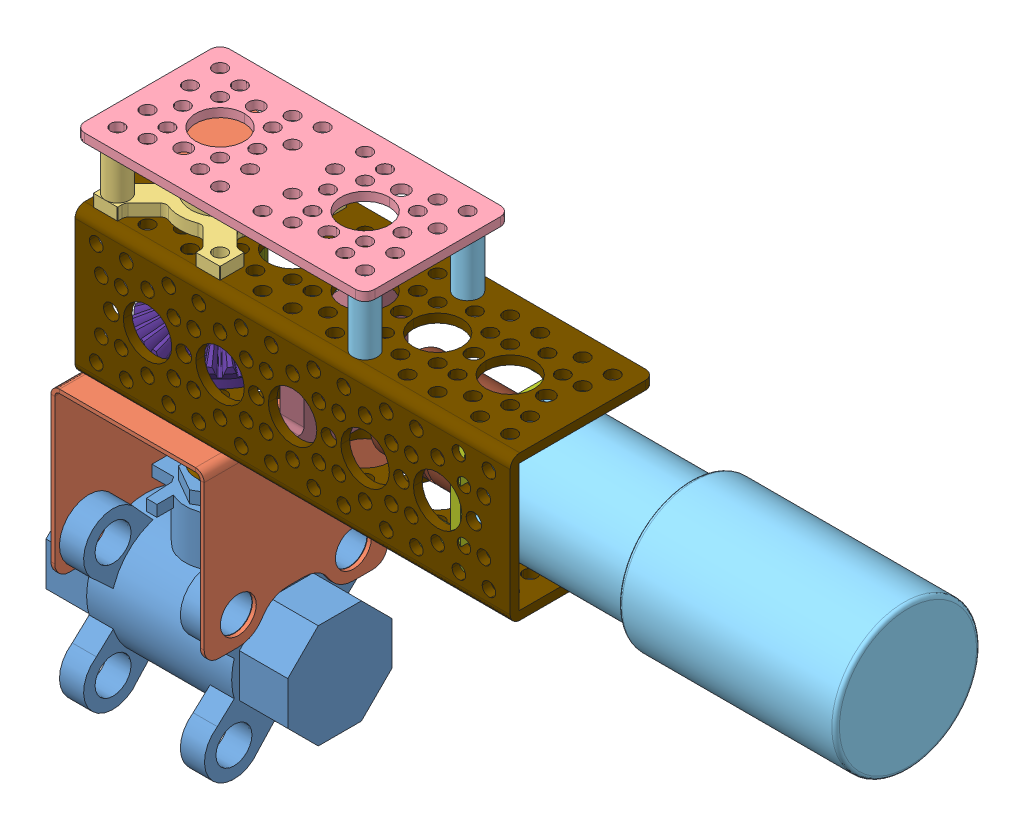
SolidWorks assembly MFV v3.1, configuration Default. Lengths in mm.
Overall size (226.04 151.59 90.41).
38 component instances, 23 part files, 48 mates.
Components (placement in the parent):
- Sharpe 39036-1: Sharpe 39036 [Default] at (-24.652 -21.0473 11.0376) size (63.5 64.02 45.72)
- Base v3-1: Base v3 [Default] at (-5.5385 29.8797 11.0376) x (0 0 1) z (1 0 0) size (48.16 44.2 40.26)
- 535110 assembly - Pillow-1: 535110 assembly - Pillow [Default] at (22.7078 53.748 4.1263) x (0 0 1) z (-1 0 0) size (33.27 5.08 33.27)
  - 535110 assembly - Pillow.STEP-1: 535110 assembly - Pillow.STEP [Default] at origin size (33.27 5.08 33.27)
    - 535110.STEP-1: 535110.STEP [Default] at (6.6273 15.2478 28.3097) size (33.27 5.08 33.27)
    - 535020.STEP-1: 535020.STEP [Default] at (6.6273 17.9338 28.3097) size (12.7 4.76 12.7)
- Motor_12VDC_638263-1: Motor_12VDC_638263 [Default] at (73.1868 50.0105 10.7536) x (0 -0.998999 -0.044744) z (0 0.044744 -0.998999) size (38 101.9 38)
- Motor_12VDC_638263_shaft-1: Motor_12VDC_638263_shaft [Default] at (73.1868 50.0105 10.7536) x (0 -0.998999 -0.044744) z (0 0.044744 -0.998999) size (6 16.2 6)
- 555188 assembly.STEP-1: 555188 assembly.STEP [Default] at (77.9607 56.4898 13.3688) x (0 1 0) z (0 0 1) size (33.4 16.56 37.36)
  - 555188.STEP-1: 555188.STEP [Default] at (-6.4793 1.7739 -2.6152) size (33.4 14.22 37.36)
  - 555188 screw_92005A116.STEP-1: 555188 screw_92005A116.STEP [Default] at (-15.6717 7.7739 6.5772) x (1 0 0) z (0 -1 0) size (6 6 8.35)
  - 555188 screw_92005A116.STEP-2: 555188 screw_92005A116.STEP [Default] at (2.7131 7.7739 6.5772) x (0 0 -1) z (0 -1 0) size (6 6 8.35)
  - 555188 screw_92005A116.STEP-3: 555188 screw_92005A116.STEP [Default] at (2.7131 7.7739 -11.8076) x (-1 0 0) z (0 -1 0) size (6 6 8.35)
  - 555188 screw_92005A116.STEP-4: 555188 screw_92005A116.STEP [Default] at (-15.6717 7.7739 -11.8076) x (0 0 1) z (0 -1 0) size (6 6 8.35)
- 625182 assembly-2: 625182 assembly [Default] at (62.7148 0.441 66.0915) x (0.514196 0 0.857672) z (-0.857672 0 0.514196) size (12.69 19.05 12.7)
- D-shaft-2.25in-1: D-shaft-2.25in [Default] at (-5.602 20.6122 10.7536) x (0.746779 0 -0.665072) z (0.665072 0 0.746779) size (6.35 57.15 7.62)
- 625100 assembly.STEP-1: 625100 assembly.STEP [Default] at (78.1702 76.4539 35.3179) x (0 0.726073 0.687617) z (-1 0 0) size (50.01 22.2 75.17)
  - 625100.STEP-1: 625100.STEP [Default] at (-36.0907 -0.3474 4.9835) size (22.23 22.2 28.57)
  - 632112_90128A121.STEP-1: 632112_90128A121.STEP [Default] at (-1.3244 -7.8756 30.0025) x (0 0 -1) z (1 0 0) size (5.61 5.61 14.62)
  - 632112_90128A121.STEP-2: 632112_90128A121.STEP [Default] at (-1.3244 -7.8756 23.5255) x (0 0 -1) z (1 0 0) size (5.61 5.61 14.62)
  - 632112_90128A121.STEP-3: 632112_90128A121.STEP [Default] at (-1.3244 -7.8756 15.0165) x (0 0 -1) z (1 0 0) size (5.61 5.61 14.62)
  - 632112_90128A121.STEP-4: 632112_90128A121.STEP [Default] at (-1.3244 -7.8756 8.5395) x (0 0 -1) z (1 0 0) size (5.61 5.61 14.62)
- 535130 assembly.STEP-1: 535130 assembly.STEP [Default] at (9.528 42.3273 39.1453) x (0 1 0) z (0 0 -1) size (33.54 6.36 33.02)
  - 535130.STEP-1: 535130.STEP [Default] at (7.6184 14.2154 28.3917) size (33.54 6.36 33.02)
  - 535020.STEP-1: 535020.STEP [Default] at (7.6184 18.1715 28.3917) size (12.7 4.76 12.7)
- 615458 assembly.STEP-1: 615458 assembly.STEP [Default] at (-48.1481 74.9588 -4.9667) x (-1 0 0) z (0 -0.723056 0.690789) size (72.51 19.24 80.12)
  - 615458.STEP-1: 615458.STEP [Default] at (-61.4441 5.8673 28.8984) size (15.1 19.24 19.22)
  - 632110_90128A121.STEP-1: 632110_90128A121.STEP [Default] at (-66.148 1.368 -6.0266) x (-0.354662 -0.934995 0) z (0 0 -1) size (5.61 5.61 13.03)
- 545309.step-1: 545309.step [Default] at (-5.602 50.6898 10.7536) x (0.920966 0 -0.389644) z (0 -1 0) size (17.78 17.76 20.07)
- 615460.step-1: 615460.step [Default] at (-5.602 40.7317 10.7536) x (0 1 0) z (-0.857986 0 0.513673) size (8.04 33.75 33.87)
- 585444-1: 585444 [Default] at (-24.652 68.9957 29.8036) x (0 -1 0) z (1 0 0) size (38.1 38.1 114.3)
- D-shaft-2in-3: D-shaft-2in [Default] at (7.4008 50.0105 10.7536) x (0 -0.983443 -0.181218) z (0 -0.181218 0.983443) size (5.71 50.8 6.35)
- AS5047 eval board-1: AS5047 eval board [Default] at (-1.127 83.6007 10.8603) size (28 1.27 22)
- 0.5in standoff-2: 0.5in standoff [Default] at (-19.0724 72.1707 -2.7168) x (0.095865 0 0.995394) z (-0.995394 0 0.095865) size (6.35 12.7 6.35)
- 0.5in standoff-4: 0.5in standoff [Default] at (-19.0724 72.1707 24.224) x (0.320114 0 -0.947379) z (0.947379 0 0.320114) size (6.35 12.7 6.35)
- 585422.step-1: 585422.step [Default] at (13.448 84.8707 10.7536) size (76.2 2.29 38.1)
- .625in standoff-1: .625in standoff [Default] at (45.9684 84.8707 24.224) x (-0.852653 0 -0.522477) z (-0.522477 0 0.852653) size (6.35 15.88 6.35)
- .625in standoff-2: .625in standoff [Default] at (45.9684 68.9957 -2.7168) x (0.998481 0 -0.055099) z (0.055099 0 0.998481) size (6.35 15.88 6.35)
Mates (geometry in assembly coordinates):
- Concentric3: concentric: circle of Sharpe 39036-1; circle of Base v3-1
- Concentric4: concentric: cylinder of Sharpe 39036-1 through (13.448 -5.9343 26.1506) axis (-1 0 0) radius 4.7307; circle of Base v3-1
- Coincident4: coincident: plane of Sharpe 39036-1 through (-24.652 -21.0473 11.0376) normal (-1 0 0); plane of Base v3-1 through (-24.652 29.8797 11.0376) normal (1 0 0)
- Concentric8: concentric: circle of Motor_12VDC_638263-1; circle of Motor_12VDC_638263_shaft-1
- Coincident8: coincident: plane of Motor_12VDC_638263-1 through (73.1868 50.0105 10.7536) normal (-1 0 0); plane of Motor_12VDC_638263_shaft-1 through (73.1868 50.0105 10.7536) normal (1 0 0)
- Concentric10: concentric: cylinder of Motor_12VDC_638263-1 through (117.9868 50.0105 10.7536) axis (-1 0 0) radius 16; circle of 555188 assembly.STEP-1/555188.STEP-1
- Distance4: distance = 2.54 mm: plane of Motor_12VDC_638263-1 through (76.1868 50.0105 10.7536) normal (-1 0 0); plane of 555188 assembly.STEP-1/555188.STEP-1 through (73.6468 50.0105 10.7536) normal (-1 0 0)
- Concentric12: concentric: cylinder of Sharpe 39036-1 through (-5.602 20.1165 10.7536) axis (0 -1 0) radius 3.937; cylinder of 625182 assembly-2 through (-5.602 29.6415 10.7536) axis (0 1 0) radius 3.175
- Distance1: distance = 0.254 mm: plane of 625182 assembly-2 through (-5.602 10.5915 10.7536) normal (0 -1 0); plane of Sharpe 39036-1 through (-5.602 10.3375 10.7536) normal (0 1 0)
- Coincident16: coincident: circle of 625182 assembly-2; plane of D-shaft-2.25in-1 through (-5.602 20.6122 10.7536) normal (0 -1 0)
- Concentric13: concentric: cylinder of 625182 assembly-2 through (-5.602 29.6415 10.7536) axis (0 1 0) radius 3.175; cylinder of D-shaft-2.25in-1 through (-5.602 77.7622 10.7536) axis (0 -1 0) radius 3.175
- Concentric20: concentric: cylinder of Motor_12VDC_638263_shaft-1 through (56.9868 50.0105 10.7536) axis (1 0 0) radius 3; cylinder of 625100 assembly.STEP-1/625100.STEP-1 through (58.8993 50.0105 10.7536) axis (-1 0 0) radius 3
- Coincident25: coincident: plane of Motor_12VDC_638263-1 through (73.1868 50.0105 10.7536) normal (-1 0 0); plane of 625100 assembly.STEP-1/625100.STEP-1 through (73.1868 50.0105 10.7536) normal (1 0 0)
- Concentric21: concentric: cylinder of D-shaft-2.25in-1 through (-5.602 77.7622 10.7536) axis (0 -1 0) radius 3.175; cylinder of 545309.step-1 through (-5.602 44.3398 10.7536) axis (0 1 0) radius 3.175
- Coincident26: coincident: cylinder of D-shaft-2.25in-1 through (-5.602 77.7622 10.7536) axis (0 -1 0) radius 3.175; circle of 615460.step-1
- Coincident28: coincident: plane of 545309.step-1 through (-5.602 44.3398 10.7536) normal (0 -1 0); plane of 615460.step-1 through (-5.602 44.3398 10.7536) normal (0 1 0)
- Concentric22: concentric: cylinder of 625100 assembly.STEP-1/625100.STEP-1 through (58.8993 50.0105 10.7536) axis (-1 0 0) radius 3; cylinder of 615458 assembly.STEP-1/615458.STEP-1 through (6.4231 50.0105 10.7536) axis (1 0 0) radius 3
- Coincident31: coincident: plane of Base v3-1 through (-5.5385 30.8957 11.0376) normal (0 1 0); plane of 585444-1 through (89.648 30.8957 -8.2964) normal (0 -1 0)
- Concentric25: concentric: cylinder of Sharpe 39036-1 through (-5.602 10.3375 10.7536) axis (0 -1 0) radius 4.6736; cylinder of 585444-1 through (-5.602 30.8957 10.7536) axis (0 -1 0) radius 6.3627
- Parallel2: parallel: plane of Base v3-1 through (-5.5385 30.8957 11.0376) normal (0 1 0); line of 585444-1 through (87.108 33.1817 -8.2964) axis (-1 0 0)
- Coincident34: coincident: plane of 535130 assembly.STEP-1/535130.STEP-1 through (30.0934 66.7097 -5.7564) normal (0 1 0); plane of 585444-1 through (89.648 66.7097 -8.2964) normal (0 -1 0)
- Concentric28: concentric: cylinder of 535130 assembly.STEP-1/535130.STEP-1 through (26.9184 66.7097 -2.7168) axis (0 1 0) radius 1.3526; cylinder of 585444-1 through (26.9184 30.8957 -2.7168) axis (0 -1 0) radius 1.778
- Concentric29: concentric: cylinder of 535130 assembly.STEP-1/535130.STEP-1 through (26.9184 66.7097 24.224) axis (0 1 0) radius 1.3526; cylinder of 585444-1 through (26.9184 30.8957 24.224) axis (0 -1 0) radius 1.778
- Parallel3: parallel: line of Base v3-1 through (-23.382 30.8957 -13.0416) axis (1 0 0); line of 585444-1 through (87.108 33.1817 -8.2964) axis (-1 0 0)
- Concentric31: concentric: circle of 555188 assembly.STEP-1/555188.STEP-1; cylinder of 585444-1 through (65.0184 30.8957 -2.7168) axis (0 -1 0) radius 1.778
- Concentric32: concentric: cylinder of 625100 assembly.STEP-1/625100.STEP-1 through (58.8993 50.0105 10.7536) axis (-1 0 0) radius 3; cylinder of D-shaft-2in-3 through (58.2008 50.0105 10.7536) axis (-1 0 0) radius 3.175
- Coincident36: coincident: plane of 625100 assembly.STEP-1/625100.STEP-1 through (58.2008 34.3204 11.1603) normal (1 0 0); plane of D-shaft-2in-3 through (58.2008 50.0105 10.7536) normal (1 0 0)
- Concentric35: concentric: cylinder of 0.5in standoff-4 through (-19.0724 84.8707 24.224) axis (0 -1 0) radius 3.175; cylinder of 585422.step-1 through (-19.0724 87.1567 24.224) axis (0 1 0) radius 1.778
- Concentric36: concentric: cylinder of 0.5in standoff-2 through (-19.0724 84.8707 -2.7168) axis (0 -1 0) radius 3.175; cylinder of 585422.step-1 through (-19.0724 87.1567 -2.7168) axis (0 1 0) radius 1.778
- Coincident42: coincident: plane of 0.5in standoff-2 through (-19.0724 84.8707 -2.7168) normal (0 1 0); plane of 585422.step-1 through (13.448 84.8707 10.7536) normal (0 -1 0)
- Coincident43: coincident: plane of 585422.step-1 through (13.448 84.8707 10.7536) normal (0 -1 0); plane of .625in standoff-2 through (45.9684 84.8707 -2.7168) normal (0 1 0)
- Concentric38: concentric: circle of 585422.step-1; cylinder of .625in standoff-2 through (45.9684 84.8707 -2.7168) axis (0 -1 0) radius 3.175
- Concentric39: concentric: cylinder of .625in standoff-1 through (45.9684 68.9957 24.224) axis (0 1 0) radius 3.175; cylinder of 585422.step-1 through (45.9684 87.1567 24.224) axis (0 1 0) radius 1.778
- Coincident44: coincident: plane of 585422.step-1 through (13.448 84.8707 10.7536) normal (0 -1 0); plane of .625in standoff-1 through (45.9684 84.8707 24.224) normal (0 1 0)
- Coincident45: coincident: plane of AS5047 eval board-1 through (-1.127 84.8707 10.8603) normal (0 1 0); plane of 585422.step-1 through (13.448 84.8707 10.7536) normal (0 -1 0)
- Parallel4: parallel: line of AS5047 eval board-1 through (-15.127 84.8707 21.8603) axis (1 0 0); plane of 585422.step-1 through (-24.652 87.1567 29.8036) normal (0 0 1)
- Distance6: distance = 8.255 mm: line of AS5047 eval board-1 through (12.873 83.6007 -0.1397) axis (-1 0 0); line of 585422.step-1 through (49.008 84.8707 -8.2964) axis (-1 0 0)
- Coincident47: coincident: plane of D-shaft-2in-3 through (7.4008 50.0105 10.7536) normal (-1 0 0); plane of 615458 assembly.STEP-1/615458.STEP-1 through (7.4008 50.0105 10.7536) normal (-1 0 0)
- Coincident48: coincident: plane of 555188 assembly.STEP-1/555188.STEP-1 through (73.6468 66.7097 27.2128) normal (0 1 0); plane of 585444-1 through (89.648 66.7097 -8.2964) normal (0 -1 0)
- Concentric40: concentric: circle of 555188 assembly.STEP-1/555188.STEP-1; cylinder of 585444-1 through (65.0184 30.8957 24.224) axis (0 -1 0) radius 1.778
- Concentric41: concentric: cylinder of 585444-1 through (-19.0724 30.8957 -2.7168) axis (0 -1 0) radius 1.778; cylinder of 0.5in standoff-2 through (-19.0724 84.8707 -2.7168) axis (0 -1 0) radius 3.175
- Coincident49: coincident: plane of 0.5in standoff-4 through (-19.0724 84.8707 24.224) normal (0 1 0); plane of 585422.step-1 through (13.448 84.8707 10.7536) normal (0 -1 0)
- Concentric42: concentric: cylinder of 585444-1 through (-19.0724 30.8957 24.224) axis (0 -1 0) radius 1.778; cylinder of 0.5in standoff-4 through (-19.0724 84.8707 24.224) axis (0 -1 0) radius 3.175
- Distance7: distance = 3.175 mm: plane of 585444-1 through (89.648 68.9957 29.8036) normal (0 1 0); plane of 0.5in standoff-4 through (-19.0724 72.1707 24.224) normal (0 -1 0)
- Distance8: distance = 9.525 mm: plane of 585422.step-1 through (-24.652 87.1567 29.8036) normal (-1 0 0); plane of AS5047 eval board-1 through (-15.127 84.8707 -0.1397) normal (-1 0 0)
- Concentric44: concentric: circle of 535110 assembly - Pillow-1/535110 assembly - Pillow.STEP-1/535110.STEP-1; cylinder of D-shaft-2.25in-1 through (-5.602 77.7622 10.7536) axis (0 -1 0) radius 3.175
- Coincident52: coincident: plane of 535110 assembly - Pillow-1/535110 assembly - Pillow.STEP-1/535110.STEP-1 through (-5.602 68.9957 10.7536) normal (0 -1 0); plane of 585444-1 through (89.648 68.9957 29.8036) normal (0 1 0)
- Concentric45: concentric: cylinder of 535110 assembly - Pillow-1/535110 assembly - Pillow.STEP-1/535110.STEP-1 through (7.8684 72.1707 -2.7168) axis (0 1 0) radius 1.778; cylinder of 585444-1 through (7.8684 30.8957 -2.7168) axis (0 -1 0) radius 1.778
